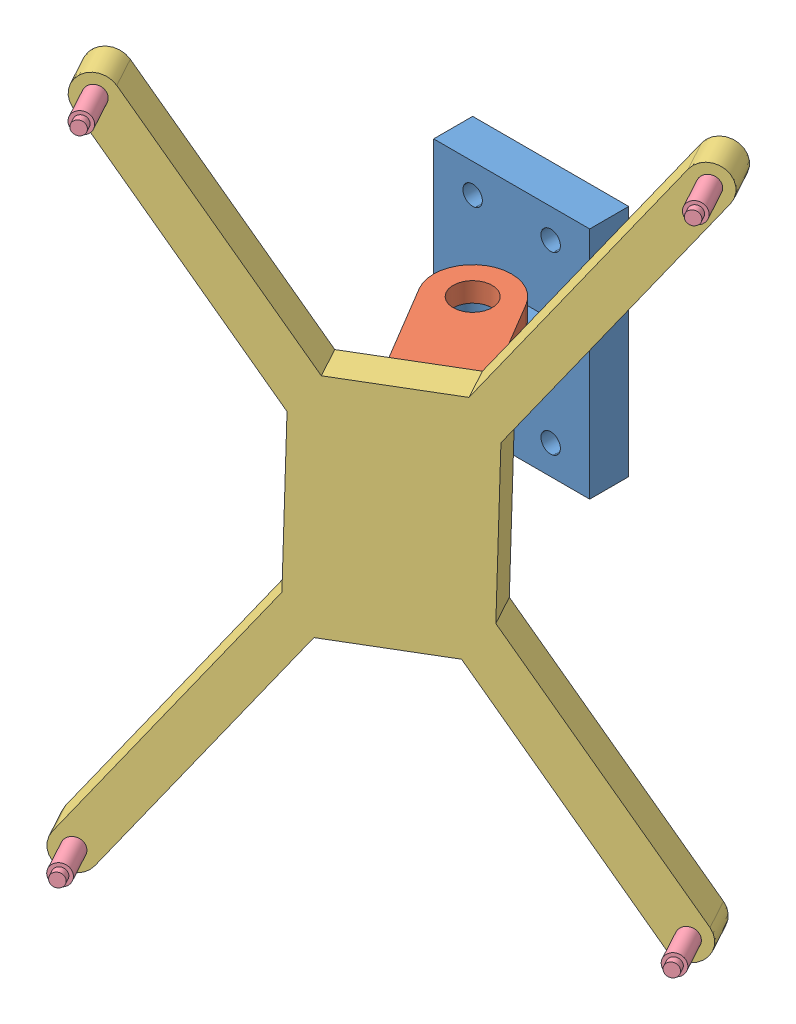
SolidWorks assembly Assemblage2, configuration Défaut. Lengths in mm.
Overall size (135.08 169.16 119.65).
7 component instances, 4 part files, 18 mates.
Components (placement in the parent):
- profile plate-1: profile plate [Défaut] at origin size (40 60 30)
- screen arm female-1: screen arm female [Défaut] at (31.8705 20 59.4853) x (-0.511573 0 -0.85924) z (0.85924 0 -0.511573) size (60 20 20)
- screen plate bis-1: screen plate bis [Défaut] at (95.9963 110.1048 35.3429) x (0.051087 -0.995001 0.085805) z (-0.509016 -0.099862 -0.854945) size (167 124.9 30)
- entretoise-1: entretoise [Défaut] at (10.3804 -45.1118 116.1435) x (0.601553 0.669153 -0.436312) z (-0.509016 -0.099862 -0.854945) size (5 5 14)
- entretoise-2: entretoise [Défaut] at (-2.7304 110.1048 94.1227) x (0.854365 0.062206 -0.515937) z (0.509016 0.099862 0.854945) size (5 5 14)
- entretoise-3: entretoise [Défaut] at (104.0169 -46.1104 48.8143) x (0.854365 0.062206 -0.515937) z (0.509016 0.099862 0.854945) size (5 5 14)
- entretoise-4: entretoise [Défaut] at (95.9963 110.1048 35.3429) x (0.854365 0.062206 -0.515937) z (0.509016 0.099862 0.854945) size (5 5 14)
Mates (geometry in assembly coordinates):
- Coïncidente1: coincident aligned: plane of profile plate-1 through (0 0 0) normal (0 0 1)
- Coïncidente2: coincident aligned: plane of profile plate-1 through (0 0 0) normal (0 1 0)
- Coïncidente3: coincident aligned: plane of profile plate-1 through (0 0 0) normal (1 0 0)
- Coaxiale1: concentric anti-aligned: cylinder of profile plate-1 through (20 25 20) axis (0 1 0) radius 5; cylinder of screen arm female-1 through (20 40 20) axis (0 -1 0) radius 5
- Coïncidente4: coincident anti-aligned: plane of profile plate-1 through (20 25 20) normal (0 -1 0); plane of screen arm female-1 through (23.4767 25 6.2919) normal (0 1 0)
- Coaxiale3: concentric anti-aligned: cylinder of screen arm female-1 through (49.0553 30 49.2539) axis (-0.85924 0 0.511573) radius 5; cylinder of screen plate bis-1 through (36.1667 30 56.9275) axis (0.85924 0 -0.511573) radius 5
- Coïncidente6: coincident anti-aligned: plane of screen arm female-1 through (41.2825 40 65.5199) normal (0.85924 0 -0.511573); plane of screen plate bis-1 through (36.1667 30 56.9275) normal (-0.85924 0 0.511573)
- Coïncidente7: coincident anti-aligned: plane of entretoise-2 through (-2.7304 110.1048 94.1227) normal (-0.509016 -0.099862 -0.854945); plane of screen plate bis-1 through (104.0169 -46.1104 48.8143) normal (0.509016 0.099862 0.854945)
- Coïncidente8: coincident anti-aligned: plane of screen plate bis-1 through (104.0169 -46.1104 48.8143) normal (0.509016 0.099862 0.854945); plane of entretoise-2 through (-2.7304 110.1048 94.1227) normal (-0.509016 -0.099862 -0.854945)
- Coaxiale4: concentric aligned: cylinder of screen plate bis-1 through (-7.8205 109.1062 85.5732) axis (0.509016 0.099862 0.854945) radius 1.75; cylinder of entretoise-2 through (-3.7484 109.9051 92.4128) axis (0.509016 0.099862 0.854945) radius 1.65
- Coaxiale5: concentric anti-aligned: cylinder of entretoise-1 through (11.3984 -44.912 117.8534) axis (-0.509016 -0.099862 -0.854945) radius 1.65; cylinder of screen plate bis-1 through (0.2001 -47.109 99.0446) axis (0.509016 0.099862 0.854945) radius 1.75
- Coïncidente9: coincident anti-aligned: plane of screen plate bis-1 through (104.0169 -46.1104 48.8143) normal (0.509016 0.099862 0.854945); plane of entretoise-1 through (5.2902 -46.1104 107.5941) normal (-0.509016 -0.099862 -0.854945)
- Coïncidente10: coincident anti-aligned: plane of screen plate bis-1 through (104.0169 -46.1104 48.8143) normal (0.509016 0.099862 0.854945); plane of entretoise-4 through (95.9963 110.1048 35.3429) normal (-0.509016 -0.099862 -0.854945)
- Coaxiale6: concentric aligned: cylinder of screen plate bis-1 through (90.9061 109.1062 26.7935) axis (0.509016 0.099862 0.854945) radius 1.75; cylinder of entretoise-4 through (94.9782 109.9051 33.633) axis (0.509016 0.099862 0.854945) radius 1.65
- Coaxiale7: concentric aligned: cylinder of screen plate bis-1 through (98.9267 -47.109 40.2649) axis (0.509016 0.099862 0.854945) radius 1.75; cylinder of entretoise-3 through (102.9988 -46.3101 47.1044) axis (0.509016 0.099862 0.854945) radius 1.65
- Coïncidente11: coincident anti-aligned: plane of screen plate bis-1 through (104.0169 -46.1104 48.8143) normal (0.509016 0.099862 0.854945); plane of entretoise-3 through (104.0169 -46.1104 48.8143) normal (-0.509016 -0.099862 -0.854945)
- AngleLimite1: limit planar angle = 2.604578 rad anti-aligned: plane of profile plate-1 through (20 0 0) normal (1 0 0); plane of screen arm female-1 through (40.4629 20 54.3696) normal (0.85924 0 -0.511573)
- AngleLimite2: limit planar angle = 0.100028 rad aligned: plane of screen arm female-1 through (31.8705 30 59.4853) normal (0 1 0); plane of screen plate bis-1 through (100.0066 31.9972 42.0786) normal (-0.051087 0.995001 -0.085805)
